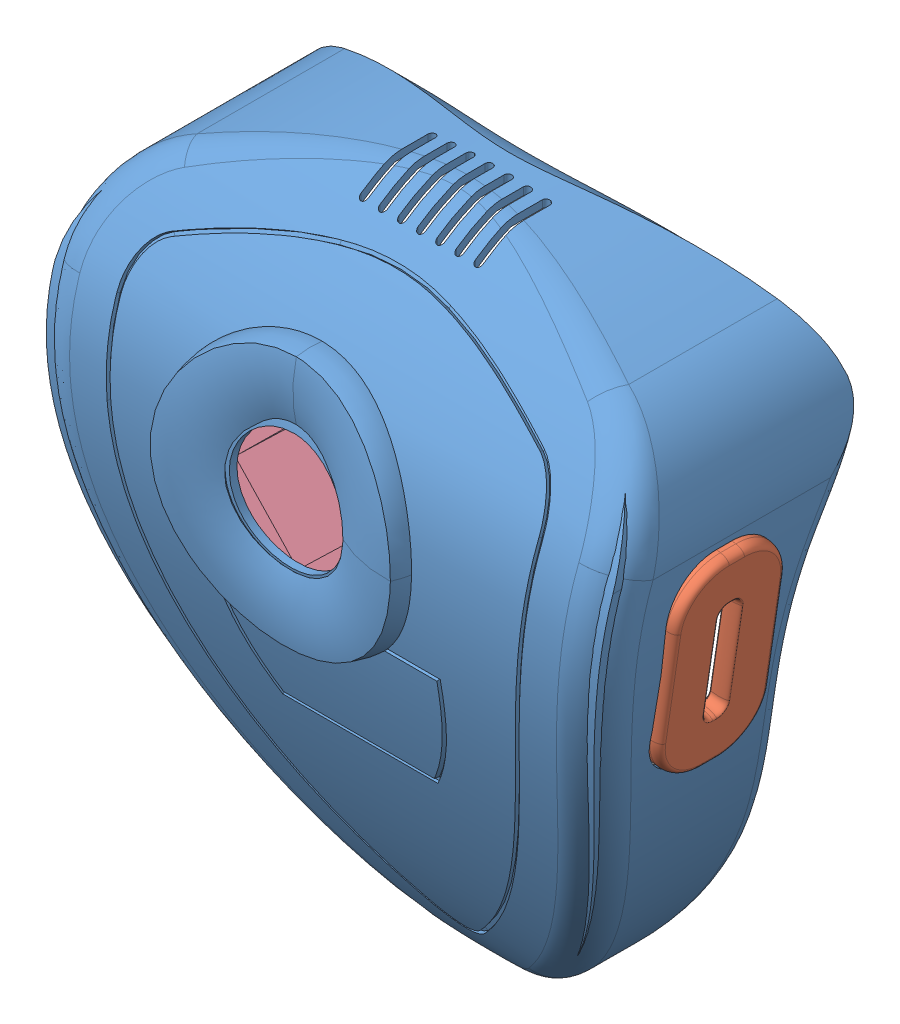
SolidWorks assembly Mochila b, configuration Default. Lengths in mm.
Overall size (340.09 384.53 166.22).
10 component instances, 5 part files, 6 mates.
Components (placement in the parent):
- backpack 2e-1: backpack 2e [Default] at (56.4158 276.023 232.3003) size (340.09 384.53 166.22)
- Part2-1: Part2 [Default] at (206.3648 280.5812 307.3003) x (0.147081 0.989124 0) z (0 0 1) size (104.05 10.05 58.05)
- Jetson H-1: Jetson H [Default] at (-88.0155 319.221 210.869) x (0.71934 0.694658 0) z (0.694632 -0.719312 0.008727) size (180 45.5 180)
  - Base-1: Base [Default] at (67.0689 90.6709 139.4266) size (180 3 180)
  - Board-1: Board [Default] at (67.0689 104.6709 139.4266) size (170 31.5 170)
  - Separador-1: Separador [Default] at (-7.9311 93.6709 214.4266) x (0.99477 0 -0.102141) z (0.102141 0 0.99477) size (6 11 6)
  - Separador-2: Separador [Default] at (142.0689 93.6709 64.4266) size (6 11 6)
  - Separador-3: Separador [Default] at (142.0689 93.6709 214.4266) size (6 11 6)
  - Separador-4: Separador [Default] at (-7.9311 93.6709 64.4266) size (6 11 6)
- Part2-3: Part2 [Default] at (-93.5333 280.5812 307.3003) x (0.14708 -0.989125 0) z (0 0 1) size (104.05 10.05 58.05)
Mates (geometry in assembly coordinates):
- Coincident1: coincident: plane of assembly; plane of assembly; plane of backpack 2e-1 through (-112.8953 254.023 336.3003) normal (0 0 -1); plane of Part2-1 through (200.4447 308.7584 336.3003) normal (0 0 1)
- Coincident2: coincident: point of assembly; point of assembly; point of backpack 2e-1; point of Part2-1
- Coincident4: coincident: curve of assembly; point of assembly; curve of backpack 2e-1; point of Part2-1
- Coincident5: coincident: plane of assembly; plane of assembly; plane of backpack 2e-1 through (-112.8953 254.023 278.3003) normal (0 0 1); plane of Part2-3 through (-79.6709 255.3456 278.3003) normal (0 0 -1)
- Coincident6: coincident: point of assembly; point of assembly; point of backpack 2e-1; point of Part2-3
- Coincident7: coincident: curve of assembly; point of assembly; curve of backpack 2e-1; point of Part2-3
